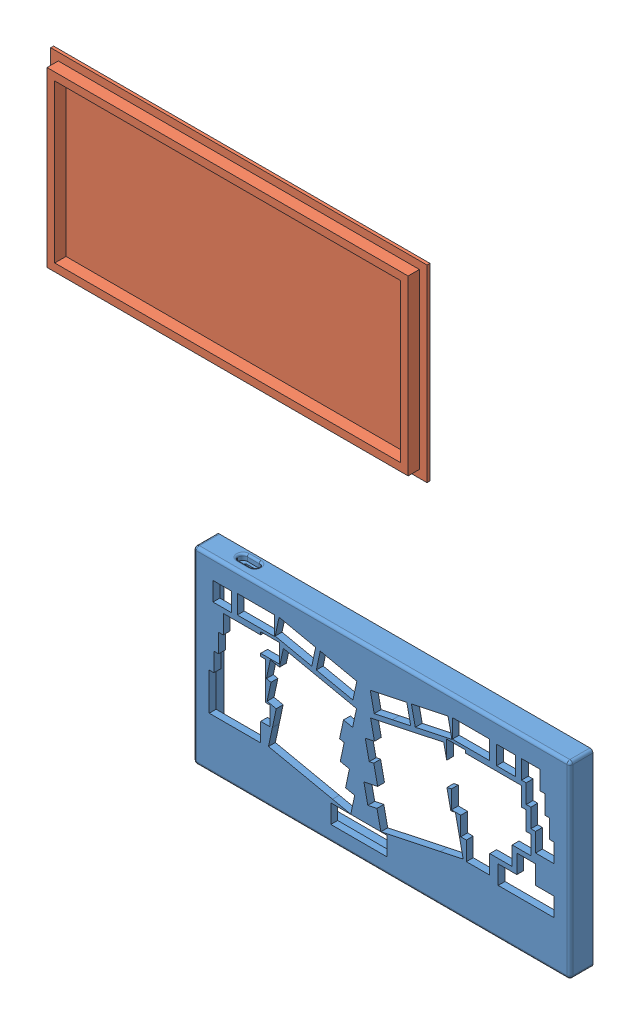
SolidWorks assembly 装配体1, configuration Default. Lengths in mm.
Overall size (522.98 564.64 41.08).
2 component instances, 2 part files, 0 mates.
Components (placement in the parent):
- 上盖V2-1: 上盖V2 [Default] at (-83.0301 100.4375 312.7316) size (383.5 192.04 23.5)
- 零件3-1: 零件3 [Default] at (-222.5292 473.0375 339.312) size (383.47 192.04 14.5)
